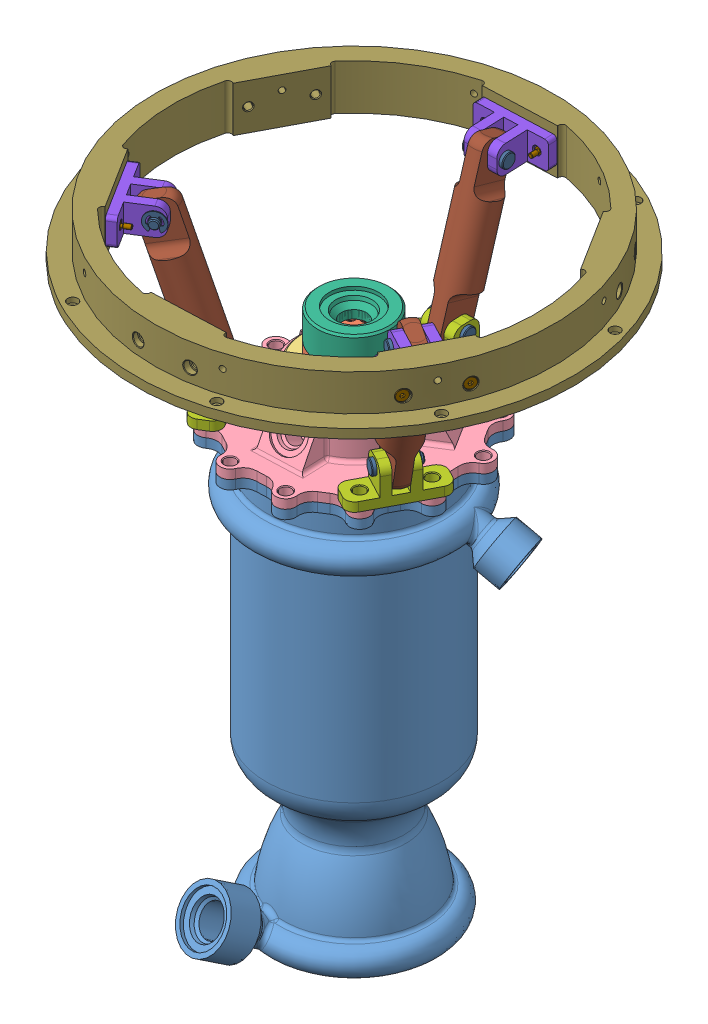
SolidWorks assembly 000014-R13_RBF, configuration Default. Lengths in mm.
Overall size (411.73 429.08 411.73).
29 component instances, 12 part files, 18 mates.
Components (placement in the parent):
- 000001-R10_RBF_TCA-1: 000001-R10_RBF_TCA [Default] at (0 98.417 0) x (0 -1 0) z (0.221168 0 -0.975236) size (296.94 259.21 181.39)
- 000015-R01_PINTLE_INJECT_ASSEM-1: 000015-R01_PINTLE_INJECT_ASSEM [Default] at (-7.2774 321.2364 87.2627) x (-0.872507 0.018417 -0.488255) z (0.488323 -0.000924 -0.872663) size (197.82 78.79 197.24)
  - 000034-R01_LOX_DIFFUSER-1: 000034-R01_LOX_DIFFUSER [Default] at (37.3755 60.1321 79.6485) x (0.750084 -0.014428 -0.661185) z (0.661086 -0.011484 0.750222) size (50.8 14.61 50.8)
  - 000032-R06_PINTLE_MIDDLE_PLATE-1: 000032-R06_PINTLE_MIDDLE_PLATE [Default] at (36.4107 7.7535 79.6969) x (0.531833 -0.009014 0.846801) z (-0.846649 0.016087 0.531909) size (72.39 48.25 72.39)
  - 000033-R08_PINTLE_BOTTOM_PLATE-1: 000033-R08_PINTLE_BOTTOM_PLATE [Default] at (36.3843 6.325 79.6982) x (0.283194 -0.00433 0.959053) z (-0.958886 0.017924 0.283225) size (158.75 34.92 158.75)
  - 000011-R04_PINTLE-1: 000011-R04_PINTLE [Default] at (36.3487 4.3885 79.7) x (-0.750084 0.014428 0.661185) z (-0.661086 0.011484 -0.750222) size (25.91 57.28 25.91)
  - 000035-R01_LOX_DOME-1: 000035-R01_LOX_DOME [Default] at (37.3521 58.8623 79.6497) x (0.99983 -0.018417 0.000009) z (0.000009 0.000924 1) size (50.8 20.32 50.8)
- 000072-R01_ENGINE_CLEVIS-1: 000072-R01_ENGINE_CLEVIS [Default] at (0 334.5067 0) x (-0.845985 0 0.533207) z (-0.533207 0 -0.845985) size (19.05 25.4 57.15)
- 000029-R01_LAUNCH_MOUNT_CLEVIS-1: 000029-R01_LAUNCH_MOUNT_CLEVIS [Default] at (-102.0681 444.4194 64.3314) x (0 1 0) z (-0.533207 0 -0.845985) size (19.05 28.57 50.8)
- SMSB5-20-1: SMSB5-20 [Default] at (-123.1976 444.4194 57.0073) x (0.845985 0 -0.533207) z (-0.003271 0.999981 -0.005189) size (29.5 8 8)
- 92735A230_GROOVED CLEVIS PIN WITH RETAINING RING-1: 92735A230_GROOVED CLEVIS PIN WITH RETAINING RING [92735A230] at (-82.4196 444.4194 53.8239) x (-0.845985 0 0.533207) z (-0.533207 0 -0.845985) size (13.39 12.33 27.94)
- 000073-R01_ENGINE_ARM-1: 000073-R01_ENGINE_ARM [Default] at (-56.6746 344.4704 35.7209) x (0.807018 0.3 -0.508647) z (0.533207 0 0.845985) size (25.4 115.42 25.4)
- 92735A230_GROOVED CLEVIS PIN WITH RETAINING RING-3: 92735A230_GROOVED CLEVIS PIN WITH RETAINING RING [92735A230] at (-58.2456 353.5567 38.5875) x (-0.845985 0 0.533207) z (-0.533207 0 -0.845985) size (13.39 12.33 27.94)
- 92735A230_GROOVED CLEVIS PIN WITH RETAINING RING-4: 92735A230_GROOVED CLEVIS PIN WITH RETAINING RING [92735A230] at (-5.403 444.4194 -98.2894) x (-0.038778 0 -0.999248) z (0.999248 0 -0.038778) size (13.39 12.33 27.94)
- 92735A230_GROOVED CLEVIS PIN WITH RETAINING RING-5: 92735A230_GROOVED CLEVIS PIN WITH RETAINING RING [92735A230] at (87.8226 444.4194 44.4655) x (0.884763 0 0.466041) z (-0.466041 0 0.884763) size (13.39 12.33 27.94)
- 000029-R01_LAUNCH_MOUNT_CLEVIS-2: 000029-R01_LAUNCH_MOUNT_CLEVIS [Default] at (-4.6786 444.4194 -120.5593) x (0 1 0) z (0.999248 0 -0.038778) size (19.05 28.57 50.8)
- 000029-R01_LAUNCH_MOUNT_CLEVIS-3: 000029-R01_LAUNCH_MOUNT_CLEVIS [Default] at (106.7467 444.4194 56.2279) x (0 1 0) z (-0.466041 0 0.884763) size (19.05 28.57 50.8)
- 000072-R01_ENGINE_CLEVIS-2: 000072-R01_ENGINE_CLEVIS [Default] at (0 334.5067 0) x (-0.038778 0 -0.999248) z (0.999248 0 -0.038778) size (19.05 25.4 57.15)
- 000072-R01_ENGINE_CLEVIS-3: 000072-R01_ENGINE_CLEVIS [Default] at (0 334.5067 0) x (0.884763 0 0.466041) z (-0.466041 0 0.884763) size (19.05 25.4 57.15)
- 92735A230_GROOVED CLEVIS PIN WITH RETAINING RING-6: 92735A230_GROOVED CLEVIS PIN WITH RETAINING RING [92735A230] at (-4.295 353.5567 -69.7359) x (-0.038778 0 -0.999248) z (0.999248 0 -0.038778) size (13.39 12.33 27.94)
- 92735A230_GROOVED CLEVIS PIN WITH RETAINING RING-7: 92735A230_GROOVED CLEVIS PIN WITH RETAINING RING [92735A230] at (62.5405 353.5567 31.1484) x (0.884763 0 0.466041) z (-0.466041 0 0.884763) size (13.39 12.33 27.94)
- 000073-R01_ENGINE_ARM-2: 000073-R01_ENGINE_ARM [Default] at (-2.5978 344.4704 -66.9421) x (0.036992 0.3 0.953222) z (-0.999248 0 0.038778) size (25.4 115.42 25.4)
- 000073-R01_ENGINE_ARM-3: 000073-R01_ENGINE_ARM [Default] at (59.2725 344.4704 31.2213) x (-0.84401 0.3 -0.444575) z (0.466041 0 -0.884763) size (25.4 115.42 25.4)
- 000066-R02_THRUST_MOUNT-1: 000066-R02_THRUST_MOUNT [Default] at (0.485 428.5444 0.2555) x (0.884763 0 0.466041) z (-0.466041 0 0.884763) size (304.8 31.75 304.8)
- SMSB5-20-3: SMSB5-20 [Default] at (-104.0903 444.4194 86.8088) x (0.845985 0 -0.533207) z (-0.003271 0.999981 -0.005189) size (29.5 8 8)
- SMSB5-20-5: SMSB5-20 [Default] at (-22.1846 444.4194 -133.5861) x (0.038778 0 0.999248) z (0.006129 0.999981 -0.000238) size (29.5 8 8)
- SMSB5-20-7: SMSB5-20 [Default] at (127.7301 444.4194 47.5438) x (-0.884763 0 -0.466041) z (-0.002859 0.999981 0.005427) size (29.5 8 8)
- SMSB5-20-10: SMSB5-20 [Default] at (13.1779 444.4194 -135.2327) x (0.038778 0 0.999248) z (0.006129 0.999981 -0.000238) size (29.5 8 8)
- SMSB5-20-12: SMSB5-20 [Default] at (111.4749 444.4194 78.9919) x (-0.884763 0 -0.466041) z (-0.002859 0.999981 0.005427) size (29.5 8 8)
Mates (geometry in assembly coordinates):
- Concentric10: concentric: cylinder of 000001-R10_RBF_TCA-1 through (0 334.8916 0) axis (0 1 0) radius 56.134; point of assembly
- Concentric22: concentric: cylinder of 000029-R01_LAUNCH_MOUNT_CLEVIS-1 through (-96.8095 444.4194 30.9929) axis (0.533207 0 0.845985) radius 3.175; cylinder of 92735A230_GROOVED CLEVIS PIN WITH RETAINING RING-1 through (-89.1913 444.4194 43.0799) axis (0.533207 0 0.845985) radius 3.175
- Coincident22: coincident: plane of 000029-R01_LAUNCH_MOUNT_CLEVIS-1 through (-83.8193 434.8944 39.694) normal (-0.533207 0 -0.845985); plane of 92735A230_GROOVED CLEVIS PIN WITH RETAINING RING-1 through (-89.1913 444.4194 43.0799) normal (0.533207 0 0.845985)
- Concentric25: concentric: cylinder of 000001-R10_RBF_TCA-1 through (-53.1339 328.1567 -49.164) axis (0 1 0) radius 4; cylinder of 000015-R01_PINTLE_INJECT_ASSEM-1/000033-R08_PINTLE_BOTTOM_PLATE-1 through (-53.1339 334.5067 -49.164) axis (0 1 0) radius 3.937
- Coincident24: coincident: axis of 000001-R10_RBF_TCA-1 through (0 116.0503 0) axis (0 1 0); plane of assembly
- Coincident25: coincident: axis of 000001-R10_RBF_TCA-1 through (0 146.5467 0) axis (0 1 0); plane of assembly
- Concentric26: concentric: cylinder of 000001-R10_RBF_TCA-1 through (0 334.8916 0) axis (0 1 0) radius 53.594; cylinder of 000015-R01_PINTLE_INJECT_ASSEM-1/000033-R08_PINTLE_BOTTOM_PLATE-1 through (0 328.1567 0) axis (0 -1 0) radius 19.939
- Coincident26: coincident: plane of 000001-R10_RBF_TCA-1 through (-77.4093 328.1567 -17.5552) normal (0 1 0); plane of 000015-R01_PINTLE_INJECT_ASSEM-1/000033-R08_PINTLE_BOTTOM_PLATE-1 through (17.5552 328.1567 -77.4093) normal (0 -1 0)
- Concentric27: concentric: cylinder of 92735A230_GROOVED CLEVIS PIN WITH RETAINING RING-1 through (-89.1913 444.4194 43.0799) axis (0.533207 0 0.845985) radius 3.175; cylinder of 000073-R01_ENGINE_ARM-1 through (-80.7267 444.4194 56.5099) axis (0.533207 0 0.845985) radius 3.175
- Concentric28: concentric: cylinder of 000072-R01_ENGINE_CLEVIS-1 through (-43.8557 353.5567 61.4185) axis (-0.533207 0 -0.845985) radius 3.175; cylinder of 000073-R01_ENGINE_ARM-1 through (-56.5527 353.5567 41.2735) axis (0.533207 0 0.845985) radius 3.175
- Coincident30: coincident: plane of 000029-R01_LAUNCH_MOUNT_CLEVIS-1 through (-75.3547 434.8944 53.124) normal (-0.533207 0 -0.845985); plane of 000073-R01_ENGINE_ARM-1 through (-93.3932 449.6957 64.4933) normal (0.533207 0 0.845985)
- Coincident31: coincident: plane of 000015-R01_PINTLE_INJECT_ASSEM-1/000033-R08_PINTLE_BOTTOM_PLATE-1 through (8.7635 334.5067 -38.6427) normal (0 1 0); plane of 000072-R01_ENGINE_CLEVIS-1 through (0 334.5067 0) normal (0 -1 0)
- Concentric33: concentric: cylinder of 000015-R01_PINTLE_INJECT_ASSEM-1/000033-R08_PINTLE_BOTTOM_PLATE-1 through (-69.1442 334.5067 21.4333) axis (0 1 0) radius 3.937; cylinder of 000072-R01_ENGINE_CLEVIS-1 through (-69.1442 340.8567 21.4333) axis (0 1 0) radius 3.937
- Concentric34: concentric: cylinder of 000015-R01_PINTLE_INJECT_ASSEM-1/000033-R08_PINTLE_BOTTOM_PLATE-1 through (-49.164 334.5067 53.1339) axis (0 1 0) radius 3.937; cylinder of 000072-R01_ENGINE_CLEVIS-1 through (-49.164 340.8567 53.1339) axis (0 1 0) radius 3.937
- Concentric35: concentric: cylinder of 000029-R01_LAUNCH_MOUNT_CLEVIS-3 through (92.9902 444.4194 68.7187) axis (-0.884763 0 -0.466041) radius 2.4574; cylinder of 000066-R02_THRUST_MOUNT-1 through (115.9482 444.4194 80.8116) axis (0.884763 0 0.466041) radius 2.5
- Concentric36: concentric: cylinder of 000029-R01_LAUNCH_MOUNT_CLEVIS-3 through (109.2667 444.4194 37.8183) axis (-0.884763 0 -0.466041) radius 2.4574; cylinder of 000066-R02_THRUST_MOUNT-1 through (132.2247 444.4194 49.9112) axis (0.884763 0 0.466041) radius 2.5
- Concentric37: concentric: cylinder of 000066-R02_THRUST_MOUNT-1 through (-108.3879 444.4194 89.5175) axis (-0.845985 0 0.533207) radius 2.5; cylinder of SMSB5-20-3 through (-87.1706 444.4194 76.1447) axis (-0.845985 0 0.533207) radius 2.5
- Coincident32: coincident: plane of 000066-R02_THRUST_MOUNT-1 through (-104.0903 446.9194 86.8088) normal (-0.845985 0 0.533207); plane of SMSB5-20-3 through (-106.2231 444.3949 83.4249) normal (0.845985 0 -0.533207)
